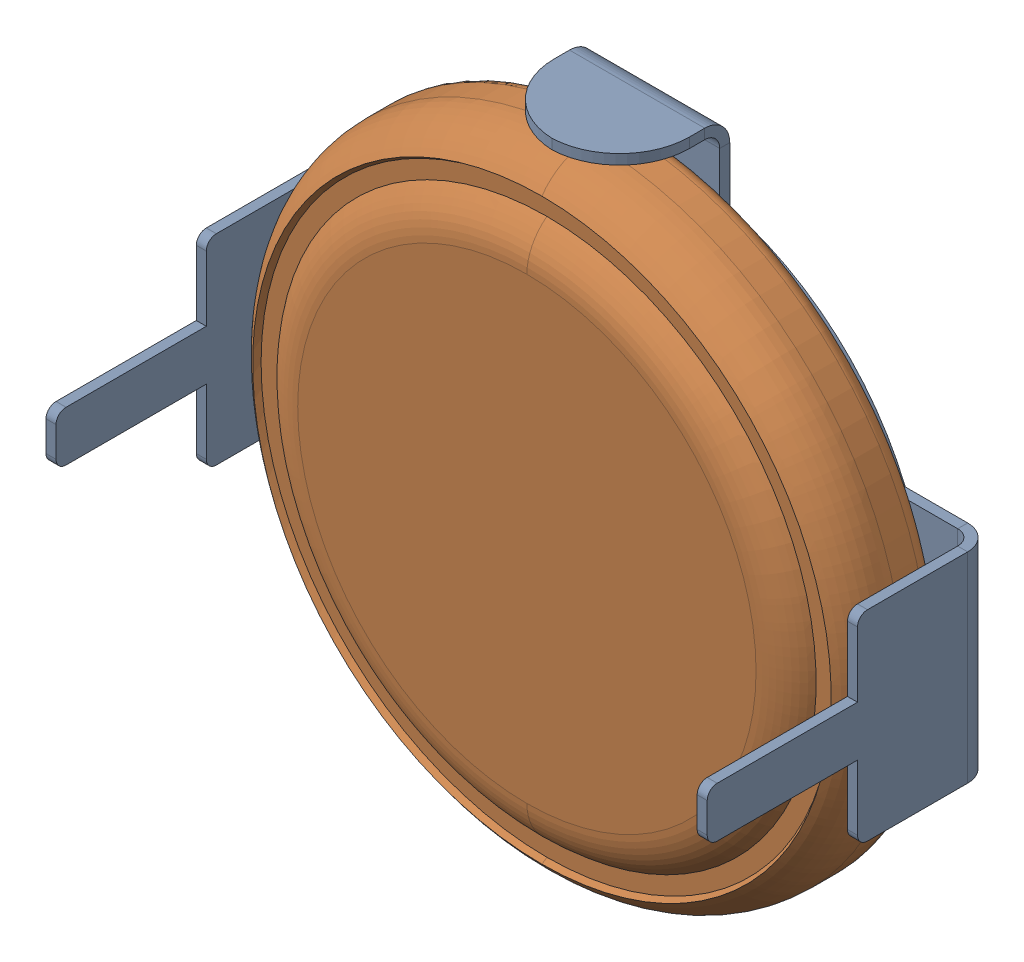
SolidWorks assembly J3, configuration Défaut. Lengths in mm.
Overall size (13.2 12.95 5.71).
2 component instances, 2 part files, 0 mates.
Components (placement in the parent):
- MY-1220-01-1: MY-1220-01 [Défaut] at (16.5 -40.2968 -0.4818) x (1 0 0) z (0 0 -1) size (13.2 11.95 5.71)
- k_cr1220_lithium-cell.stp-1: k_cr1220_lithium-cell.stp [Défaut] at (16.5 -40.2968 -2.0818) x (0 0 1) z (1 0 0) size (2.05 12.55 12.55)
